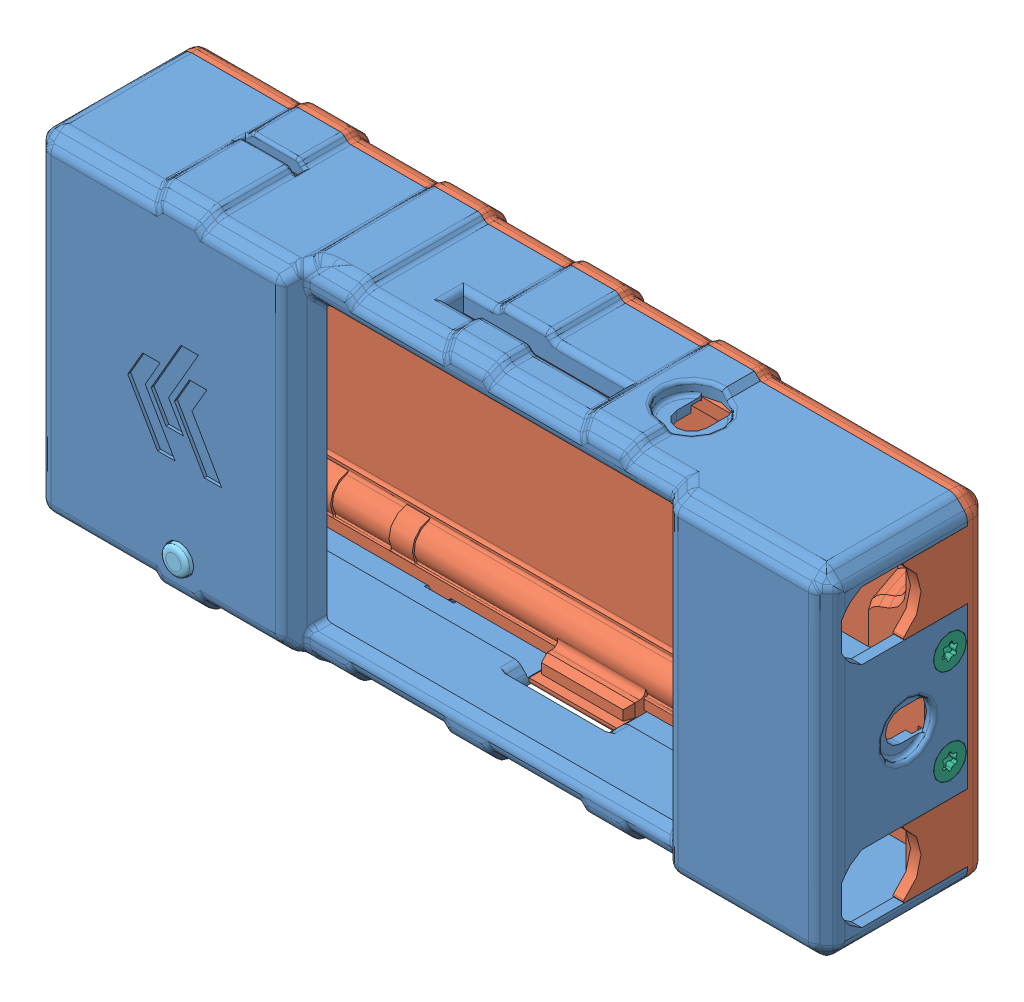
SolidWorks assembly CASE_ASSEMBLED_NO_PCB, configuration Default. Lengths in mm.
Overall size (136 60.9 30.43).
10 component instances, 6 part files, 21 mates.
Components (placement in the parent):
- TOP_COVER-2: TOP_COVER [Default] at (33.0085 -2.6049 38.1704) x (0 1 0) z (1 0 0) size (60.9 24.14 136)
- BOTTOM_COVER_FIX-1: BOTTOM_COVER_FIX [Default] at (33.0085 -2.6049 33.3704) x (0 1 0) z (1 0 0) size (60.06 16.3 136)
- STYLUS-1: STYLUS [Default] at (33.0085 3.3951 37.7704) x (0 -1 0) z (0 0 1) size (5.1 88 7.3)
- F2-B-M3-Pressfit_2-1: F2-B-M3-Pressfit_2 [Default] at (37.7936 26.3952 41.1703) x (0 -0.381849 0.924225) z (0 -0.924225 -0.381849) size (5.4 4.81 5.4)
- F2-B-M3-Pressfit_2-2: F2-B-M3-Pressfit_2 [Default] at (164.2233 34.5701 41.1705) x (0 0.381849 -0.924225) z (0 -0.924225 -0.381849) size (5.4 4.81 5.4)
- F2-B-M3-Pressfit_2-3: F2-B-M3-Pressfit_2 [Default] at (164.2233 18.2201 41.1705) x (0 0.381849 -0.924225) z (0 -0.924225 -0.381849) size (5.4 4.81 5.4)
- BUTTON-1: BUTTON [Default] at (58.1285 3.3951 63.3004) x (-1 0 0) z (0 -1 0) size (7.1 14.91 7.1)
- hexa csunk flathd screw_iso-1: hexa csunk flathd screw_iso [ISO 14581 M3x8x8-S] at (33.0085 26.3951 41.1704) x (0 -0.003299 0.999995) z (-1 0 0) size (5.5 5.5 8)
- hexa csunk flathd screw_iso-2: hexa csunk flathd screw_iso [ISO 14581 M3x8x8-S] at (169.0085 34.5701 41.1704) x (0 -0.763708 0.645562) z (1 0 0) size (5.5 5.5 8)
- hexa csunk flathd screw_iso-3: hexa csunk flathd screw_iso [ISO 14581 M3x8x8-S] at (169.0085 18.2201 41.1704) x (0 0 -1) z (1 0 0) size (5.5 5.5 8)
Mates (geometry in assembly coordinates):
- Distance7: distance = 0.2 mm anti-aligned: plane of TIK_PCB_20220619-3 through (37.0085 53.3951 44.167) normal (0 1 0); plane of TOP_COVER-2 through (167.2085 53.5951 58.3004) normal (0 -1 0)
- Distance8: distance = 0.2 mm anti-aligned: plane of TIK_PCB_20220619-3 through (167.0085 51.3951 44.167) normal (1 0 0); plane of TOP_COVER-2 through (167.2085 -0.8049 58.3004) normal (-1 0 0)
- Coincident21: coincident anti-aligned: plane of TOP_COVER-2 through (33.0085 -2.6049 58.3004) normal (0 0 -1); plane of TIK_PCB_20220619-3 through (141.9113 51.3271 58.3004) normal (0 0 1)
- Coincident26: coincident anti-aligned: plane of TOP_COVER-2 through (33.0085 -2.6049 38.1704) normal (0 0 -1); plane of BOTTOM_COVER-1 through (33.0085 -2.6049 38.1704) normal (0 0 1)
- Coincident24: coincident aligned: plane of TOP_COVER-2 through (33.0085 -2.6049 62.3004) normal (-1 0 0); plane of BOTTOM_COVER-1 through (33.0085 -2.6049 38.1704) normal (-1 0 0)
- Coincident25: coincident aligned: plane of TOP_COVER-2 through (33.0085 55.3951 62.3004) normal (0 1 0); plane of BOTTOM_COVER-1 through (33.0085 55.3951 38.1704) normal (0 1 0)
- Coincident28: coincident aligned: plane of TOP_COVER-2 through (33.0085 -2.6049 62.3004) normal (-1 0 0); plane of STYLUS-1 through (33.0085 3.3951 37.7704) normal (-1 0 0)
- Concentric1: concentric aligned: cylinder of BOTTOM_COVER-1 through (123.0085 3.3951 37.7704) axis (-1 0 0) radius 2.65; cylinder of STYLUS-1 through (121.0085 3.3951 37.7704) axis (-1 0 0) radius 2.5
- Concentric6: concentric aligned: cylinder of BOTTOM_COVER-1 through (42.0085 26.3951 41.1704) axis (-1 0 0) radius 2; cylinder of F2-B-M3-Pressfit_2-1 through (33.9545 26.3951 41.1704) axis (-1 0 0) radius 2.6978
- Distance9: distance = 0.1 mm aligned: plane of BOTTOM_COVER-1 through (35.0085 39.3951 44.1704) normal (-1 0 0); plane of F2-B-M3-Pressfit_2-1 through (34.9085 25.8807 42.4153) normal (-1 0 0)
- Concentric7: concentric aligned: cylinder of BOTTOM_COVER-1 through (160.0085 34.5701 41.1704) axis (1 0 0) radius 2; cylinder of F2-B-M3-Pressfit_2-2 through (168.0624 34.5701 41.1704) axis (1 0 0) radius 2.6978
- Distance10: distance = 0.1 mm aligned: plane of F2-B-M3-Pressfit_2-2 through (167.1085 35.0844 39.9255) normal (1 0 0); plane of BOTTOM_COVER-1 through (167.0085 28.9951 44.1704) normal (1 0 0)
- Concentric8: concentric aligned: cylinder of BOTTOM_COVER-1 through (160.0085 18.2201 41.1704) axis (1 0 0) radius 2; cylinder of F2-B-M3-Pressfit_2-3 through (168.0624 18.2201 41.1704) axis (1 0 0) radius 2.6978
- Distance11: distance = 0.1 mm aligned: plane of F2-B-M3-Pressfit_2-3 through (167.1085 18.7344 39.9255) normal (1 0 0); plane of BOTTOM_COVER-1 through (167.0085 12.6451 44.1704) normal (1 0 0)
- Concentric9: concentric aligned: cylinder of TOP_COVER-2 through (58.1285 3.3951 51.2293) axis (0 0 1) radius 2.5; cylinder of BUTTON-1 through (58.1285 3.3951 58.3004) axis (0 0 1) radius 2.3
- Parallel1: parallel anti-aligned: plane of TOP_COVER-2 through (58.8785 -0.4049 69.0484) normal (0 1 0); plane of BUTTON-1 through (57.8285 -0.1549 49.3004) normal (0 -1 0)
- Coincident36: coincident anti-aligned: plane of TOP_COVER-2 through (33.0085 -2.6049 58.3004) normal (0 0 -1); plane of BUTTON-1 through (58.1285 3.3951 58.3004) normal (0 0 1)
- Concentric10: concentric anti-aligned: cylinder of TOP_COVER-2 through (159.0085 34.5701 41.1704) axis (1 0 0) radius 1.55; cylinder of hexa csunk flathd screw_iso-2 through (169.0085 34.5701 41.1704) axis (-1 0 0) radius 2.75
- Coincident39: coincident aligned: cone of TOP_COVER-2 through (168.7085 34.5701 41.1704) axis (-1 0 0); cone of hexa csunk flathd screw_iso-2 through (167.3585 34.5701 41.1704) axis (-1 0 0)
- Coincident40: coincident aligned: cone of TOP_COVER-2 through (168.7085 18.2201 41.1704) axis (-1 0 0); cone of hexa csunk flathd screw_iso-3 through (167.3585 18.2201 41.1704) axis (-1 0 0)
- Coincident41: coincident aligned: cone of TOP_COVER-2 through (33.3085 26.3951 41.1704) axis (1 0 0); cone of hexa csunk flathd screw_iso-1 through (34.6585 26.3951 41.1704) axis (1 0 0)
